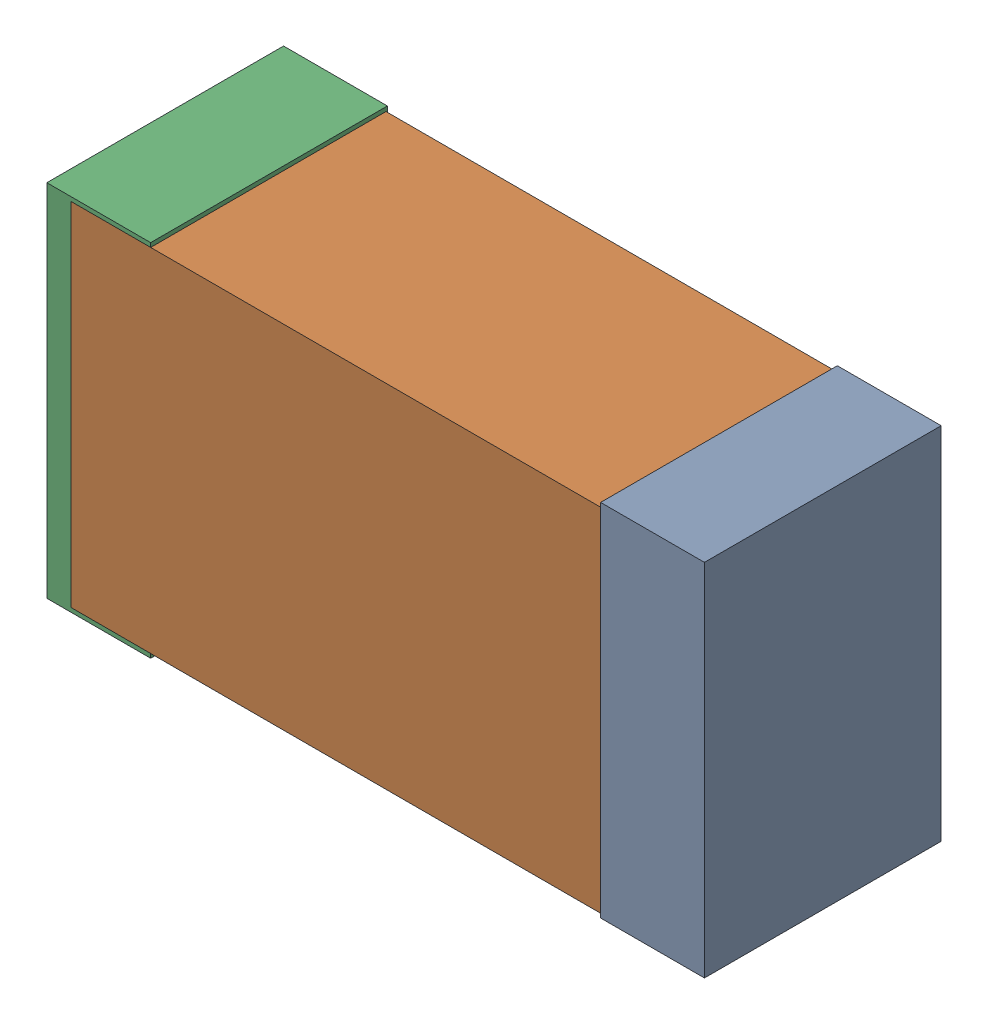
SolidWorks assembly USB45_FB2, configuration Default. Lengths in mm.
Overall size (2.38 1.3 0.85).
6 component instances, 2 part files, 0 mates.
Components (placement in the parent):
- 384311232-1: 384311232 [Default] at (163.814 38.735 -1.9574) size (0.38 1.3 0.85)
  - Extruded_8-1: Extruded_8 [Default] at origin size (0.38 1.3 0.85)
- 384311360-1: 384311360 [Default] at (162.814 38.735 -1.9524) size (2.2 1.27 0.85)
  - Extruded_9-1: Extruded_9 [Default] at origin size (2.2 1.27 0.85)
- 384311232-2: 384311232 [Default] at (161.814 38.735 -1.9574) size (0.38 1.3 0.85)
  - Extruded_8-1: Extruded_8 [Default] at origin size (0.38 1.3 0.85)
